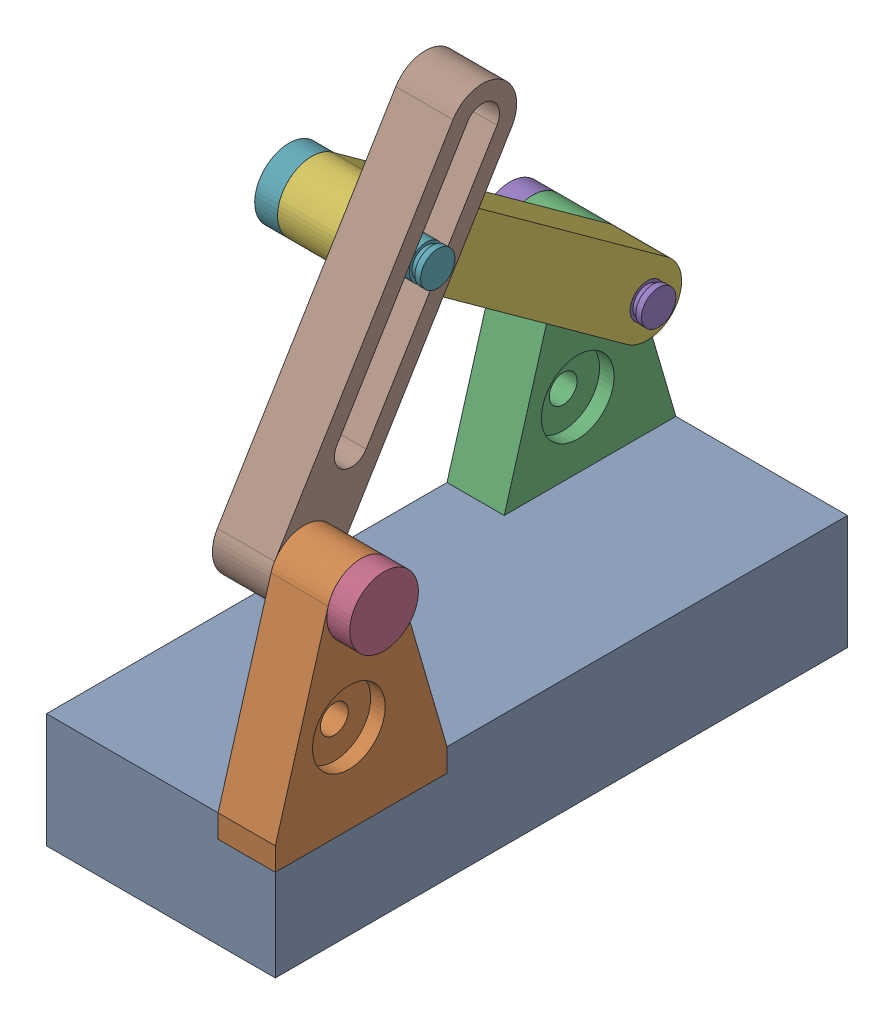
SolidWorks assembly lever arm, configuration Default. Lengths in mm.
Overall size (24 54.75 50).
8 component instances, 5 part files, 17 mates.
Components (placement in the parent):
- Base-1: Base [Default] at (-4.9558 7.4002 47.5875) size (20 10 50)
- Support-1: Support [Default] at (10.0442 17.4002 47.5875) x (0 0 -1) z (1 0 0) size (15 20 5)
- Support-2: Support [Default] at (-4.9558 17.4002 12.5875) x (0 0 -1) z (1 0 0) size (15 20 5)
- Pin-1: Pin [Default] at (4.0442 32.4002 40.0875) size (13 6 6)
- Pin-2: Pin [Default] at (6.0442 32.4002 5.0875) x (-1 0 0) z (0 0.595008 -0.80372) size (13 6 6)
- Crank-1: Crank [Default] at (0.0442 49.987 29.3919) x (0 -0.586225 -0.810148) z (1 0 0) size (36 6 5)
- Pin-4: Pin [Default] at (11.0442 49.987 29.3919) x (-1 0 0) z (0 0.26494 -0.964265) size (13 6 6)
- Rocker-1: Rocker [Long] at (5.0442 32.4002 40.0875) x (0 0.854402 -0.519613) z (1 0 0) size (36 6 5)
Mates (geometry in assembly coordinates):
- Coincident1: coincident anti-aligned: plane of Base-1 through (-4.9558 15.4002 47.5875) normal (0 1 0); plane of Support-1 through (15.0442 15.4002 47.5875) normal (0 -1 0)
- Coincident3: coincident anti-aligned: line of Base-1 through (10.0442 15.4002 32.5875) axis (0 0 1); line of Support-1 through (10.0442 15.4002 47.5875) axis (0 0 -1)
- Coincident5: coincident aligned: line of Base-1 through (15.0442 15.4002 32.5875) axis (-1 0 0); line of Support-1 through (15.0442 15.4002 32.5875) axis (-1 0 0)
- Coincident6: coincident anti-aligned: plane of Base-1 through (-4.9558 15.4002 47.5875) normal (0 1 0); plane of Support-2 through (0.0442 15.4002 12.5875) normal (0 -1 0)
- Coincident7: coincident anti-aligned: line of Base-1 through (-4.9558 15.4002 12.5875) axis (1 0 0); line of Support-2 through (0.0442 15.4002 12.5875) axis (-1 0 0)
- Coincident8: coincident anti-aligned: line of Base-1 through (-4.9558 15.4002 -2.4125) axis (0 0 1); line of Support-2 through (-4.9558 15.4002 12.5875) axis (0 0 -1)
- Coincident10: coincident anti-aligned: plane of Support-1 through (15.0442 32.4002 40.0875) normal (1 0 0); plane of Pin-1 through (15.0442 32.4002 37.0875) normal (-1 0 0)
- Concentric2: concentric aligned: cylinder of Support-1 through (15.0442 32.4002 40.0875) axis (-1 0 0) radius 1.5; cylinder of Pin-1 through (4.0442 32.4002 40.0875) axis (-1 0 0) radius 1.5
- Coincident12: coincident anti-aligned: plane of Support-2 through (-4.9558 32.4002 5.0875) normal (-1 0 0); plane of Pin-2 through (-4.9558 30.6152 7.4986) normal (1 0 0)
- Concentric4: concentric anti-aligned: cylinder of Support-2 through (0.0442 32.4002 5.0875) axis (-1 0 0) radius 1.5; cylinder of Pin-2 through (6.0442 32.4002 5.0875) axis (1 0 0) radius 1.5
- Coincident13: coincident anti-aligned: plane of Support-2 through (0.0442 32.4002 5.0875) normal (1 0 0); plane of Crank-1 through (0.0442 49.987 29.3919) normal (-1 0 0)
- Concentric5: concentric anti-aligned: cylinder of Pin-2 through (6.0442 32.4002 5.0875) axis (1 0 0) radius 1.5; cylinder of Crank-1 through (5.0442 32.4002 5.0875) axis (-1 0 0) radius 1.5
- Coincident14: coincident anti-aligned: plane of Crank-1 through (0.0442 49.987 29.3919) normal (-1 0 0); plane of Pin-4 through (0.0442 49.1922 32.2847) normal (1 0 0)
- Concentric6: concentric anti-aligned: cylinder of Crank-1 through (5.0442 49.987 29.3919) axis (-1 0 0) radius 1.5; cylinder of Pin-4 through (11.0442 49.987 29.3919) axis (1 0 0) radius 1.5
- Coincident15: coincident anti-aligned: plane of Support-1 through (10.0442 32.4002 40.0875) normal (-1 0 0); plane of Rocker-1 through (10.0442 32.4002 40.0875) normal (1 0 0)
- Concentric7: concentric aligned: cylinder of Pin-1 through (4.0442 32.4002 40.0875) axis (-1 0 0) radius 1.5; cylinder of Rocker-1 through (10.0442 32.4002 40.0875) axis (-1 0 0) radius 1.5
- Slot1: slot anti-aligned: cylinder of Pin-4 through (11.0442 49.987 29.3919) axis (1 0 0) radius 1.5; plane of Rocker-1 through (10.0442 57.2529 23.2175) normal (0 0.519613 0.854402); cylinder of Rocker-1 through (10.0442 39.2355 35.9306) axis (-1 0 0) radius 1.5
